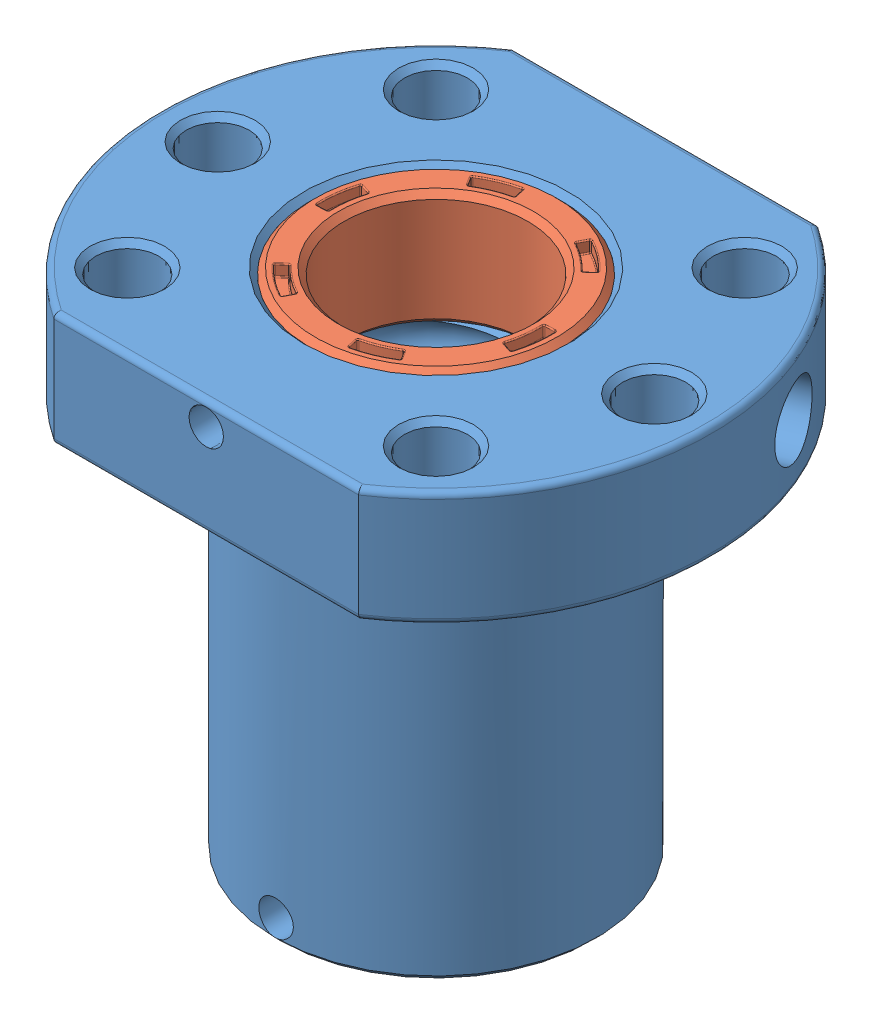
SolidWorks assembly Ballscrew Nut SFU1605-1610, configuration SFU1605-3. Lengths in mm.
Overall size (48 44 40).
3 component instances, 3 part files, 5 mates.
Components (placement in the parent):
- SFU1605-1610-1-1: SFU1605-1610-1 [Default] at (-14 43.5 0) size (48 44 40)
- SFU1605-1610-3-1: SFU1605-1610-3 [Default] at (-14 33.4998 0) x (-0.92388 0 0.382683) z (-0.382683 0 -0.92388) size (22.05 10 22)
- SFU1605-1610-2-1: SFU1605-1610-2 [Default] at (-14 9.5 0) x (1 0 0) z (0 0 -1) size (22 10 22)
Mates (geometry in assembly coordinates):
- Concentric1: concentric: cylinder of SFU1605-1610-1-1 through (-14 43.5 0) axis (0 1 0) radius 11; cylinder of SFU1605-1610-3-1 through (-14 43.4998 0) axis (0 -1 0) radius 11
- Concentric3: concentric: cylinder of SFU1605-1610-1-1 through (-41.5576 38.4998 11.4147) axis (0.92388 0 -0.382683) radius 2.5; cylinder of SFU1605-1610-3-1 through (-3.8364 38.4998 -4.2099) axis (-0.92388 0 0.382683) radius 2.5
- Coincident1: coincident: plane of SFU1605-1610-1-1 through (-14 9.5 8) normal (0 -1 0); plane of SFU1605-1610-2-1 through (-14 9.5 0) normal (0 1 0)
- Concentric4: concentric: cylinder of SFU1605-1610-1-1 through (-14 43.5 0) axis (0 1 0) radius 11; cylinder of SFU1605-1610-2-1 through (-14 -0.5 0) axis (0 1 0) radius 11
- Coincident4: coincident: point of SFU1605-1610-1-1
